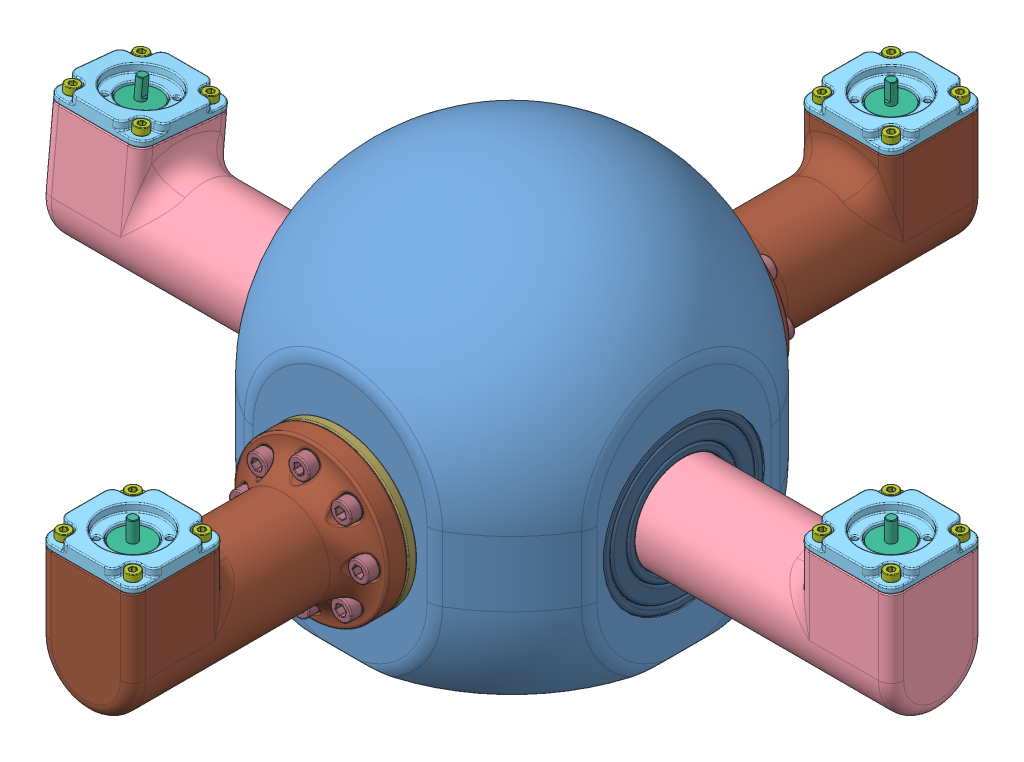
SolidWorks assembly Full_Assembly, configuration Default. Lengths in mm.
Overall size (360.06 147.08 360.06).
84 component instances, 16 part files, 14 mates.
Components (placement in the parent):
- Main_Body_Assembly-1: Main_Body_Assembly [Default] at origin size (149.49 192.5 149.49) (flexible)
  - Main_Top-1: Main_Top [Default] at origin size (148.79 147.08 148.79)
  - Main_Bottom-1: Main_Bottom [Default] at origin size (143.6 42.5 143.6) (hidden)
  - Main_Seal-1: Main_Seal [Default] at origin size (149.49 6.96 149.49) (hidden)
  - Arm_Static_Nut-1: Arm_Static_Nut [Default] at (0 25.0625 -70) x (1 0 0) z (0 -1 0) size (9.16 5.42 8) (hidden)
  - Arm_Static_Nut-2: Arm_Static_Nut [Default] at (0 25.0625 70) x (1 0 0) z (0 1 0) size (9.16 5.42 8) (hidden)
  - Arm_Static_Nut-3: Arm_Static_Nut [Default] at (-17.7219 17.7219 70) x (0.707107 0.707107 0) z (-0.707107 0.707107 0) size (9.16 5.42 8) (hidden)
  - Arm_Static_Nut-4: Arm_Static_Nut [Default] at (-25.0625 0 70) x (0 1 0) z (-1 0 0) size (9.16 5.42 8) (hidden)
  - Arm_Static_Nut-5: Arm_Static_Nut [Default] at (-17.7219 -17.7219 70) x (-0.707107 0.707107 0) z (-0.707107 -0.707107 0) size (9.16 5.42 8) (hidden)
  - Arm_Static_Nut-6: Arm_Static_Nut [Default] at (0 -25.0625 70) x (-1 0 0) z (0 -1 0) size (9.16 5.42 8) (hidden)
  - Arm_Static_Nut-7: Arm_Static_Nut [Default] at (17.7219 -17.7219 70) x (-0.707107 -0.707107 0) z (0.707107 -0.707107 0) size (9.16 5.42 8) (hidden)
  - Arm_Static_Nut-8: Arm_Static_Nut [Default] at (25.0625 0 70) x (0 -1 0) z (1 0 0) size (9.16 5.42 8) (hidden)
  - Arm_Static_Nut-9: Arm_Static_Nut [Default] at (17.7219 17.7219 70) x (0.707107 -0.707107 0) z (0.707107 0.707107 0) size (9.16 5.42 8) (hidden)
  - Arm_Static_Nut-10: Arm_Static_Nut [Default] at (-17.7219 17.7219 -70) x (0.707107 0.707107 0) z (0.707107 -0.707107 0) size (9.16 5.42 8) (hidden)
  - Arm_Static_Nut-11: Arm_Static_Nut [Default] at (-25.0625 0 -70) x (0 1 0) z (1 0 0) size (9.16 5.42 8) (hidden)
  - Arm_Static_Nut-12: Arm_Static_Nut [Default] at (-17.7219 -17.7219 -70) x (-0.707107 0.707107 0) z (0.707107 0.707107 0) size (9.16 5.42 8) (hidden)
  - Arm_Static_Nut-13: Arm_Static_Nut [Default] at (0 -25.0625 -70) x (-1 0 0) z (0 1 0) size (9.16 5.42 8) (hidden)
  - Arm_Static_Nut-14: Arm_Static_Nut [Default] at (17.7219 -17.7219 -70) x (-0.707107 -0.707107 0) z (-0.707107 0.707107 0) size (9.16 5.42 8) (hidden)
  - Arm_Static_Nut-15: Arm_Static_Nut [Default] at (25.0625 0 -70) x (0 -1 0) z (-1 0 0) size (9.16 5.42 8) (hidden)
  - Arm_Static_Nut-16: Arm_Static_Nut [Default] at (17.7219 17.7219 -70) x (0.707107 -0.707107 0) z (-0.707107 -0.707107 0) size (9.16 5.42 8) (hidden)
  - Nema_8_Short-1: Nema_8_Short [Default] at (-44.25 26.875 0) x (0 0.707107 0.707107) z (0 -0.707107 0.707107) size (22 40 20)
  - Nema_Gear-2: Nema_Gear [Default] at (-51 26.875 0) x (0 0.707107 -0.707107) z (0 -0.707107 -0.707107) size (14.96 10.01 14.93)
- Rotating_Arm_Assembly-3: Rotating_Arm_Assembly [Default] at (-146.5662 -63.3046 -129.4672) x (1 0 0) z (0 0.09582 0.995399) size (137.03 84.24 83.48) (flexible)
  - Rotating_Prop_Arm-1: Rotating_Prop_Arm [Default] at (6.5662 50.6078 134.9373) x (0 -1 0) z (0 0 1) size (52.38 122.25 39.75)
  - Prop_Top_Plate-2: Prop_Top_Plate [Default] at (-13.3088 85.6078 134.9373) size (40.31 5.75 40.31)
  - Bearing-1: Bearing [Default] at (81.5662 50.6078 134.9373) x (0 0.262788 -0.964854) z (0 0.964854 0.262788) size (68 15 68) (hidden)
  - Nema_8-1: Nema_8 [Default] at (-13.3088 83.1078 134.9373) size (22 48 20)
  - Prop_Plate_Bolt-5: Prop_Plate_Bolt [Default] at (-27.8713 88.6078 149.4998) x (-1 0 0) z (0 0 1) size (5.75 19.35 5.75)
  - Prop_Plate_Bolt-6: Prop_Plate_Bolt [Default] at (-27.8713 88.6078 120.3748) x (-1 0 0) z (0 0 1) size (5.75 19.35 5.75)
  - Prop_Plate_Bolt-7: Prop_Plate_Bolt [Default] at (1.2537 88.6078 120.3748) x (-1 0 0) z (0 0 1) size (5.75 19.35 5.75)
  - Prop_Plate_Bolt-8: Prop_Plate_Bolt [Default] at (1.2537 88.6078 149.4998) x (-1 0 0) z (0 0 1) size (5.75 19.35 5.75)
  - Arm_Gear-5: Arm_Gear [Default] at (95.5662 50.6078 134.9373) x (0 0 1) z (0 -1 0) size (41.65 11.51 41.66)
  - Gear_Bolt-5: Gear_Bolt [Default] at (103.5662 64.2953 134.9373) x (0 0.995399 0.09582) z (0 -0.09582 0.995399) size (5.75 23.37 5.75)
  - Gear_Bolt-9: Gear_Bolt [Default] at (103.5662 50.6078 121.2498) x (0 0.09582 -0.995399) z (0 0.995399 0.09582) size (5.75 23.37 5.75)
  - Gear_Bolt-10: Gear_Bolt [Default] at (103.5662 36.9203 134.9373) x (0 -0.995399 -0.09582) z (0 0.09582 -0.995399) size (5.75 23.37 5.75)
  - Gear_Bolt-11: Gear_Bolt [Default] at (103.5662 50.6078 148.6248) x (0 -0.09582 0.995399) z (0 -0.995399 -0.09582) size (5.75 23.37 5.75)
- Rotating_Arm_Assembly-4: Rotating_Arm_Assembly [Default] at (146.5662 -50.6078 134.9373) x (-1 0 0) z (0 0 -1) size (137.03 81.76 78.52) (flexible)
  - Rotating_Prop_Arm-1: Rotating_Prop_Arm [Default] at (6.5662 50.6078 134.9373) x (0 -1 0) z (0 0 1) size (52.38 122.25 39.75)
  - Prop_Top_Plate-2: Prop_Top_Plate [Default] at (-13.3088 85.6078 134.9373) size (40.31 5.75 40.31)
  - Bearing-1: Bearing [Default] at (81.5662 50.6078 134.9373) x (0 0.169126 -0.985594) z (0 0.985594 0.169126) size (68 15 68)
  - Nema_8-1: Nema_8 [Default] at (-13.3088 83.1078 134.9373) size (22 48 20)
  - Prop_Plate_Bolt-5: Prop_Plate_Bolt [Default] at (-27.8713 88.6078 149.4998) x (-1 0 0) z (0 0 1) size (5.75 19.35 5.75)
  - Prop_Plate_Bolt-6: Prop_Plate_Bolt [Default] at (-27.8713 88.6078 120.3748) x (-1 0 0) z (0 0 1) size (5.75 19.35 5.75)
  - Prop_Plate_Bolt-7: Prop_Plate_Bolt [Default] at (1.2537 88.6078 120.3748) x (-1 0 0) z (0 0 1) size (5.75 19.35 5.75)
  - Prop_Plate_Bolt-8: Prop_Plate_Bolt [Default] at (1.2537 88.6078 149.4998) x (-1 0 0) z (0 0 1) size (5.75 19.35 5.75)
  - Arm_Gear-5: Arm_Gear [Default] at (95.5662 50.6078 134.9373) x (0 0 1) z (0 -1 0) size (41.65 11.51 41.66)
  - Gear_Bolt-5: Gear_Bolt [Default] at (103.5662 64.2953 134.9373) x (0 1 0) z (0 0 1) size (5.75 23.37 5.75)
  - Gear_Bolt-9: Gear_Bolt [Default] at (103.5662 50.6078 121.2498) x (0 0 -1) z (0 1 0) size (5.75 23.37 5.75)
  - Gear_Bolt-10: Gear_Bolt [Default] at (103.5662 36.9203 134.9373) x (0 -1 0) z (0 0 -1) size (5.75 23.37 5.75)
  - Gear_Bolt-11: Gear_Bolt [Default] at (103.5662 50.6078 148.6248) x (0 0 1) z (0 -1 0) size (5.75 23.37 5.75)
- Static_Arm_Assembly-3: Static_Arm_Assembly [Default] at (-80.415 -54.138 130.871) x (0 0 -1) z (1 0 0) size (115.55 75 65)
  - Static_Prop_Arm-2: Static_Prop_Arm [Default] at (-9.129 54.138 80.415) x (0 -1 0) z (0 0 1) size (65 103.5 65)
  - Prop_Top_Plate-1: Prop_Top_Plate [Default] at (-29.004 89.138 80.415) size (40.31 5.75 40.31)
  - Static_Prop_Arm_Seal-1: Static_Prop_Arm_Seal [Default] at (56.496 54.138 80.415) x (0 1 0) z (0 0 1) size (65 3.75 65)
  - Nema_8-1: Nema_8 [Default] at (-29.004 86.638 80.415) size (22 48 20)
  - Prop_Plate_Bolt-1: Prop_Plate_Bolt [Default] at (-43.5665 92.138 94.9775) x (-1 0 0) z (0 0 1) size (5.75 19.35 5.75)
  - Prop_Plate_Bolt-2: Prop_Plate_Bolt [Default] at (-43.5665 92.138 65.8525) x (-1 0 0) z (0 0 1) size (5.75 19.35 5.75)
  - Prop_Plate_Bolt-3: Prop_Plate_Bolt [Default] at (-14.4415 92.138 65.8525) x (-1 0 0) z (0 0 1) size (5.75 19.35 5.75)
  - Prop_Plate_Bolt-4: Prop_Plate_Bolt [Default] at (-14.4415 92.138 94.9775) x (-1 0 0) z (0 0 1) size (5.75 19.35 5.75)
  - Mount_Bolt-1: Mount_Bolt [Default] at (40.871 79.2005 80.415) x (0 -1 0) z (0 0 1) size (8.75 25.52 8.75)
  - Mount_Bolt-2: Mount_Bolt [Default] at (40.871 71.8599 98.1369) x (0 -0.707107 -0.707107) z (0 -0.707107 0.707107) size (8.75 25.52 8.75)
  - Mount_Bolt-3: Mount_Bolt [Default] at (40.871 54.138 105.4775) x (0 0 -1) z (0 -1 0) size (8.75 25.52 8.75)
  - Mount_Bolt-4: Mount_Bolt [Default] at (40.871 36.4162 98.1369) x (0 0.707107 -0.707107) z (0 -0.707107 -0.707107) size (8.75 25.52 8.75)
  - Mount_Bolt-5: Mount_Bolt [Default] at (40.871 29.0755 80.415) x (0 1 0) z (0 0 -1) size (8.75 25.52 8.75)
  - Mount_Bolt-6: Mount_Bolt [Default] at (40.871 36.4162 62.6932) x (0 0.707107 0.707107) z (0 0.707107 -0.707107) size (8.75 25.52 8.75)
  - Mount_Bolt-7: Mount_Bolt [Default] at (40.871 54.138 55.3525) x (0 0 1) z (0 1 0) size (8.75 25.52 8.75)
  - Mount_Bolt-8: Mount_Bolt [Default] at (40.871 71.8599 62.6932) x (0 -0.707107 0.707107) z (0 0.707107 0.707107) size (8.75 25.52 8.75)
- Static_Arm_Assembly-4: Static_Arm_Assembly [Default] at (80.415 -54.138 -130.871) x (0 0 1) z (-1 0 0) size (115.55 75 65)
  - Static_Prop_Arm-2: Static_Prop_Arm [Default] at (-9.129 54.138 80.415) x (0 -1 0) z (0 0 1) size (65 103.5 65)
  - Prop_Top_Plate-1: Prop_Top_Plate [Default] at (-29.004 89.138 80.415) size (40.31 5.75 40.31)
  - Static_Prop_Arm_Seal-1: Static_Prop_Arm_Seal [Default] at (56.496 54.138 80.415) x (0 1 0) z (0 0 1) size (65 3.75 65)
  - Nema_8-1: Nema_8 [Default] at (-29.004 86.638 80.415) size (22 48 20)
  - Prop_Plate_Bolt-1: Prop_Plate_Bolt [Default] at (-43.5665 92.138 94.9775) x (-1 0 0) z (0 0 1) size (5.75 19.35 5.75)
  - Prop_Plate_Bolt-2: Prop_Plate_Bolt [Default] at (-43.5665 92.138 65.8525) x (-1 0 0) z (0 0 1) size (5.75 19.35 5.75)
  - Prop_Plate_Bolt-3: Prop_Plate_Bolt [Default] at (-14.4415 92.138 65.8525) x (-1 0 0) z (0 0 1) size (5.75 19.35 5.75)
  - Prop_Plate_Bolt-4: Prop_Plate_Bolt [Default] at (-14.4415 92.138 94.9775) x (-1 0 0) z (0 0 1) size (5.75 19.35 5.75)
  - Mount_Bolt-1: Mount_Bolt [Default] at (40.871 79.2005 80.415) x (0 -1 0) z (0 0 1) size (8.75 25.52 8.75)
  - Mount_Bolt-2: Mount_Bolt [Default] at (40.871 71.8599 98.1369) x (0 -0.707107 -0.707107) z (0 -0.707107 0.707107) size (8.75 25.52 8.75)
  - Mount_Bolt-3: Mount_Bolt [Default] at (40.871 54.138 105.4775) x (0 0 -1) z (0 -1 0) size (8.75 25.52 8.75)
  - Mount_Bolt-4: Mount_Bolt [Default] at (40.871 36.4162 98.1369) x (0 0.707107 -0.707107) z (0 -0.707107 -0.707107) size (8.75 25.52 8.75)
  - Mount_Bolt-5: Mount_Bolt [Default] at (40.871 29.0755 80.415) x (0 1 0) z (0 0 -1) size (8.75 25.52 8.75)
  - Mount_Bolt-6: Mount_Bolt [Default] at (40.871 36.4162 62.6932) x (0 0.707107 0.707107) z (0 0.707107 -0.707107) size (8.75 25.52 8.75)
  - Mount_Bolt-7: Mount_Bolt [Default] at (40.871 54.138 55.3525) x (0 0 1) z (0 1 0) size (8.75 25.52 8.75)
  - Mount_Bolt-8: Mount_Bolt [Default] at (40.871 71.8599 62.6932) x (0 -0.707107 0.707107) z (0 0.707107 0.707107) size (8.75 25.52 8.75)
Mates (geometry in assembly coordinates):
- Coincident6: coordinate: point of ?
- Coincident7: coincident: plane of ? through (0 0 0) normal (0 0 1); plane of assembly through (0 0 0) normal (0 0 1)
- Coincident8: coincident: plane of ? through (0 0 0) normal (0 1 0); plane of assembly through (0 0 0) normal (0 1 0)
- Coincident9: coincident: plane of ? through (0 0 0) normal (1 0 0); plane of assembly through (0 0 0) normal (1 0 0)
- Concentric1: concentric: cylinder of ? through (-72.5 0 0) axis (1 0 0) radius 34; cylinder of Rotating_Arm_Assembly-3/Bearing-1 through (-72.5 0 0) axis (1 0 0) radius 34
- Coincident16: coincident: plane of ? through (-57.5 0 0) normal (1 0 0); plane of Rotating_Arm_Assembly-3/Bearing-1 through (-57.5 0 0) normal (1 0 0)
- Concentric2: concentric: cylinder of ? through (-72.5 0 0) axis (1 0 0) radius 34; cylinder of Rotating_Arm_Assembly-4/Bearing-1 through (72.5 0 0) axis (-1 0 0) radius 34
- Coincident18: coincident: plane of ? through (57.5 0 0) normal (-1 0 0); plane of Rotating_Arm_Assembly-4/Bearing-1 through (57.5 0 0) normal (-1 0 0)
- Coincident20: coincident: plane of ? through (0 0 72.5) normal (0 0 1); plane of Static_Arm_Assembly-3/Static_Prop_Arm_Seal-1 through (0 0 72.5) normal (0 0 -1)
- Concentric3: concentric: cylinder of ? through (0 0 -72.5) axis (0 0 1) radius 7.5; cylinder of Static_Arm_Assembly-3/Static_Prop_Arm-2 through (0 0 85) axis (0 0 -1) radius 32.5
- Parallel4: parallel: plane of Static_Arm_Assembly-3 through (-80.415 -54.138 130.871) normal (1 0 0); plane of assembly through (0 0 0) normal (1 0 0)
- Coincident22: coincident: plane of ? through (0 0 -72.5) normal (0 0 -1); plane of Static_Arm_Assembly-4/Static_Prop_Arm_Seal-1 through (0 0 -72.5) normal (0 0 1)
- Concentric4: concentric: cylinder of ? through (0 0 -72.5) axis (0 0 1) radius 7.5; cylinder of Static_Arm_Assembly-4/Static_Prop_Arm-2 through (0 0 -85) axis (0 0 1) radius 32.5
- Parallel5: parallel: plane of Static_Arm_Assembly-4 through (80.415 -54.138 -130.871) normal (-1 0 0); plane of assembly through (0 0 0) normal (1 0 0)
